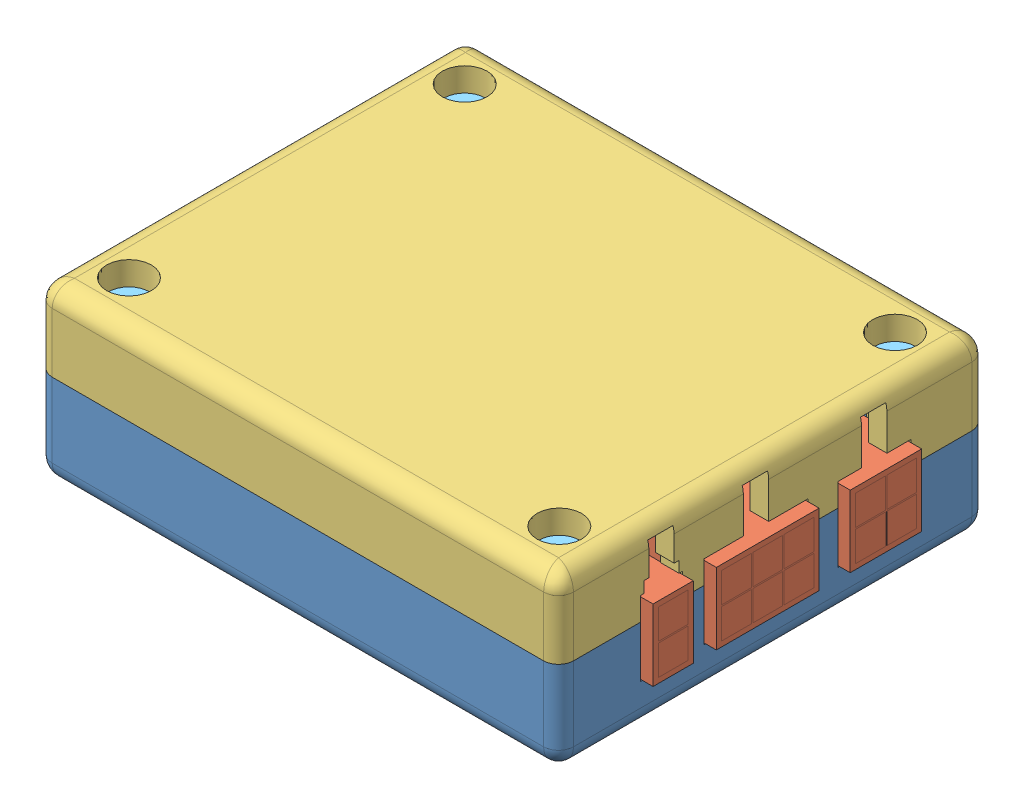
SolidWorks assembly Housing, configuration Standard. Lengths in mm.
Overall size (73.14 23 57.5).
11 component instances, 5 part files, 37 mates.
Components (placement in the parent):
- Housing-Bottom-1: Housing-Bottom [Standard] at (-70 0 57.5) size (70 12.5 57.5)
- Audio-Switch-1: Audio-Switch [Standard] at (-67.0675 4.8 54.4675) x (1 0 0) z (0 1 0) size (73.14 51.44 13.69)
- Housing-Top-1: Housing-Top [Standard] at (-70 20.5 57.5) size (70 17.4 57.5)
- hex thin nut chamfered gradeab_din-1: hex thin nut chamfered gradeab_din [Hexagon Thin Nut ISO 4035 - M3 - S] at (-63.8925 2 51.2925) x (1 0 0) z (0 1 0) size (5.5 6.35 1.8)
- hex thin nut chamfered gradeab_din-2: hex thin nut chamfered gradeab_din [Hexagon Thin Nut ISO 4035 - M3 - S] at (-63.8925 2 6.2075) x (1 0 0) z (0 1 0) size (5.5 6.35 1.8)
- hex thin nut chamfered gradeab_din-3: hex thin nut chamfered gradeab_din [Hexagon Thin Nut ISO 4035 - M3 - S] at (-6.1075 2 6.2075) x (1 0 0) z (0 1 0) size (5.5 6.35 1.8)
- hex thin nut chamfered gradeab_din-4: hex thin nut chamfered gradeab_din [Hexagon Thin Nut ISO 4035 - M3 - S] at (-6.1075 2 51.2925) x (1 0 0) z (0 1 0) size (5.5 6.35 1.8)
- countersunk flat head cross recess screw_din-1: countersunk flat head cross recess screw_din [DIN EN ISO 7046-1 - M3 x 20 - Z - 20S] at (-6.1075 20 6.2075) x (0 -1 0) z (0 0 1) size (20 5.5 5.5)
- countersunk flat head cross recess screw_din-2: countersunk flat head cross recess screw_din [DIN EN ISO 7046-1 - M3 x 20 - Z - 20S] at (-6.1075 20 51.2925) x (0 -1 0) z (0 0 1) size (20 5.5 5.5)
- countersunk flat head cross recess screw_din-3: countersunk flat head cross recess screw_din [DIN EN ISO 7046-1 - M3 x 20 - Z - 20S] at (-63.8925 20 6.2075) x (0 -1 0) z (0 0 1) size (20 5.5 5.5)
- countersunk flat head cross recess screw_din-4: countersunk flat head cross recess screw_din [DIN EN ISO 7046-1 - M3 x 20 - Z - 20S] at (-63.8925 20 51.2925) x (0 -1 0) z (0 0 1) size (20 5.5 5.5)
Mates (geometry in assembly coordinates):
- Deckungsgleich4: coincident anti-aligned: plane of Housing-Bottom-1 through (-63.8925 4 51.2925) normal (0 1 0); plane of Audio-Switch-1 through (-67.0675 4 54.4675) normal (0 -1 0)
- Deckungsgleich5: coincident anti-aligned: plane of Housing-Bottom-1 through (-68 12.5 2) normal (0 1 0); plane of Housing-Top-1 through (-70 12.5 57.5) normal (0 -1 0)
- Deckungsgleich6: coincident aligned: plane of Housing-Bottom-1 through (-70 2.5 55.5) normal (-1 0 0); plane of Housing-Top-1 through (-70 23 55.5) normal (-1 0 0)
- Deckungsgleich7: coincident aligned: plane of Housing-Bottom-1 through (-68 2.5 57.5) normal (0 0 1); plane of Housing-Top-1 through (-68 23 57.5) normal (0 0 1)
- Deckungsgleich8: coincident anti-aligned: plane of Housing-Top-1 through (-63.46 20 5.675) normal (0 1 0); plane of ? through (-60.71 20 5.675) normal (0 -1 0)
- Deckungsgleich9: coincident anti-aligned: plane of Housing-Top-1 through (-63.46 20 50.76) normal (0 1 0); plane of ? through (-60.71 20 50.76) normal (0 -1 0)
- Deckungsgleich10: coincident anti-aligned: plane of Housing-Top-1 through (-5.675 20 5.675) normal (0 1 0); plane of ? through (-2.925 20 5.675) normal (0 -1 0)
- Deckungsgleich11: coincident anti-aligned: plane of Housing-Top-1 through (-5.675 20 50.76) normal (0 1 0); plane of ? through (-2.925 20 50.76) normal (0 -1 0)
- Konzentrisch1: concentric anti-aligned: cylinder of Housing-Top-1 through (-63.46 23 5.675) axis (0 -1 0) radius 1.5; cylinder of ? through (-63.46 54.75 5.675) axis (0 1 0) radius 1.5
- Konzentrisch2: concentric anti-aligned: cylinder of Housing-Top-1 through (-63.46 23 50.76) axis (0 -1 0) radius 1.5; cylinder of ? through (-63.46 54.75 50.76) axis (0 1 0) radius 1.5
- Konzentrisch3: concentric anti-aligned: cylinder of Housing-Top-1 through (-5.675 23 5.675) axis (0 -1 0) radius 1.5; cylinder of ? through (-5.675 54.75 5.675) axis (0 1 0) radius 1.5
- Konzentrisch4: concentric anti-aligned: cylinder of Housing-Top-1 through (-5.675 23 50.76) axis (0 -1 0) radius 1.5; cylinder of ? through (-5.675 54.75 50.76) axis (0 1 0) radius 1.5
- Deckungsgleich12: coincident anti-aligned: plane of Housing-Bottom-1 through (-70 2 57.5) normal (0 -1 0); plane of hex thin nut chamfered gradeab_din-4 through (-6.1075 2 48.1171) normal (0 1 0)
- Deckungsgleich13: coincident anti-aligned: plane of Housing-Bottom-1 through (-70 2 57.5) normal (0 -1 0); plane of hex thin nut chamfered gradeab_din-3 through (-6.1075 2 3.0321) normal (0 1 0)
- Deckungsgleich15: coincident anti-aligned: plane of Housing-Bottom-1 through (-70 2 57.5) normal (0 -1 0); plane of hex thin nut chamfered gradeab_din-1 through (-63.8925 2 48.1171) normal (0 1 0)
- Deckungsgleich16: coincident anti-aligned: plane of Housing-Bottom-1 through (-70 2 57.5) normal (0 -1 0); plane of hex thin nut chamfered gradeab_din-2 through (-63.8925 2 3.0321) normal (0 1 0)
- Deckungsgleich17: coincident anti-aligned: plane of Housing-Bottom-1 through (-3.3575 2 49.7048) normal (-1 0 0); plane of hex thin nut chamfered gradeab_din-4 through (-3.3575 0.2 49.7048) normal (1 0 0)
- Deckungsgleich18: coincident anti-aligned: plane of Housing-Bottom-1 through (-3.3575 2 52.8802) normal (-0.5 0 -0.866025); plane of hex thin nut chamfered gradeab_din-4 through (-6.1075 0.2 54.4679) normal (0.5 0 0.866025)
- Deckungsgleich19: coincident anti-aligned: plane of Housing-Bottom-1 through (-6.1075 2 3.0321) normal (-0.5 0 0.866025); plane of hex thin nut chamfered gradeab_din-3 through (-3.3575 0.2 4.6198) normal (0.5 0 -0.866025)
- Deckungsgleich20: coincident anti-aligned: plane of Housing-Bottom-1 through (-8.8575 2 4.6198) normal (0.5 0 0.866025); plane of hex thin nut chamfered gradeab_din-3 through (-6.1075 0.2 3.0321) normal (-0.5 0 -0.866025)
- Deckungsgleich21: coincident anti-aligned: plane of Housing-Bottom-1 through (-63.8925 2 48.1171) normal (-0.5 0 0.866025); plane of hex thin nut chamfered gradeab_din-1 through (-61.1425 0.2 49.7048) normal (0.5 0 -0.866025)
- Deckungsgleich22: coincident anti-aligned: plane of Housing-Bottom-1 through (-61.1425 2 49.7048) normal (-1 0 0); plane of hex thin nut chamfered gradeab_din-1 through (-61.1425 0.2 49.7048) normal (1 0 0)
- Deckungsgleich23: coincident anti-aligned: plane of Housing-Bottom-1 through (-61.1425 2 7.7952) normal (-0.5 0 -0.866025); plane of hex thin nut chamfered gradeab_din-2 through (-63.8925 0.2 9.3829) normal (0.5 0 0.866025)
- Deckungsgleich24: coincident anti-aligned: plane of Housing-Bottom-1 through (-61.1425 2 4.6198) normal (-1 0 0); plane of hex thin nut chamfered gradeab_din-2 through (-61.1425 0.2 4.6198) normal (1 0 0)
- Deckungsgleich25: coincident anti-aligned: plane of Housing-Bottom-1 through (-2 0 55.5) normal (0 -1 0); plane of assembly through (0 0 0) normal (0 1 0)
- Deckungsgleich26: coincident anti-aligned: plane of Housing-Bottom-1 through (-68 2.5 0) normal (0 0 -1); plane of assembly through (0 0 0) normal (0 0 1)
- Deckungsgleich27: coincident aligned: plane of Housing-Bottom-1 through (0 2.5 55.5) normal (1 0 0); plane of assembly through (0 0 0) normal (1 0 0)
- Deckungsgleich28: coincident aligned: cone of Housing-Top-1 through (-63.8925 18.45 51.2925) axis (0 -1 0); cone of countersunk flat head cross recess screw_din-4 through (-63.8925 19.6 51.2925) axis (0 -1 0)
- Deckungsgleich29: coincident aligned: cone of Housing-Top-1 through (-63.8925 18.45 6.2075) axis (0 -1 0); cone of countersunk flat head cross recess screw_din-3 through (-63.8925 19.6 6.2075) axis (0 -1 0)
- Deckungsgleich30: coincident aligned: cone of Housing-Top-1 through (-6.1075 18.45 6.2075) axis (0 -1 0); cone of countersunk flat head cross recess screw_din-1 through (-6.1075 19.6 6.2075) axis (0 -1 0)
- Deckungsgleich31: coincident aligned: cone of Housing-Top-1 through (-6.1075 18.45 51.2925) axis (0 -1 0); cone of countersunk flat head cross recess screw_din-2 through (-6.1075 19.6 51.2925) axis (0 -1 0)
- Parallel1: parallel: line of Housing-Top-1 through (-67.5 23 55) axis (1 0 0); plane of countersunk flat head cross recess screw_din-2 through (-6.6054 17.99 51.6625) normal (0 0 -1)
- Parallel2: parallel: line of Housing-Top-1 through (-67.5 23 55) axis (1 0 0); plane of countersunk flat head cross recess screw_din-4 through (-64.3904 17.99 51.6625) normal (0 0 -1)
- Parallel4: parallel: line of Housing-Top-1 through (-2.5 23 2.5) axis (-1 0 0); plane of countersunk flat head cross recess screw_din-3 through (-63.3946 17.99 5.8375) normal (0 0 1)
- Parallel5: parallel: line of Housing-Top-1 through (-2.5 23 2.5) axis (-1 0 0); plane of countersunk flat head cross recess screw_din-1 through (-5.6096 17.99 5.8375) normal (0 0 1)
- Konzentrisch5: concentric aligned: cylinder of Housing-Bottom-1 through (-63.8925 2.5 51.2925) axis (0 -1 0) radius 1.5; cylinder of Audio-Switch-1 through (-63.8925 4 51.2925) axis (0 -1 0) radius 1.55
- Konzentrisch6: concentric aligned: cylinder of Housing-Bottom-1 through (-6.1075 2.5 6.2075) axis (0 -1 0) radius 1.5; cylinder of Audio-Switch-1 through (-6.1075 4 6.2075) axis (0 -1 0) radius 1.55
